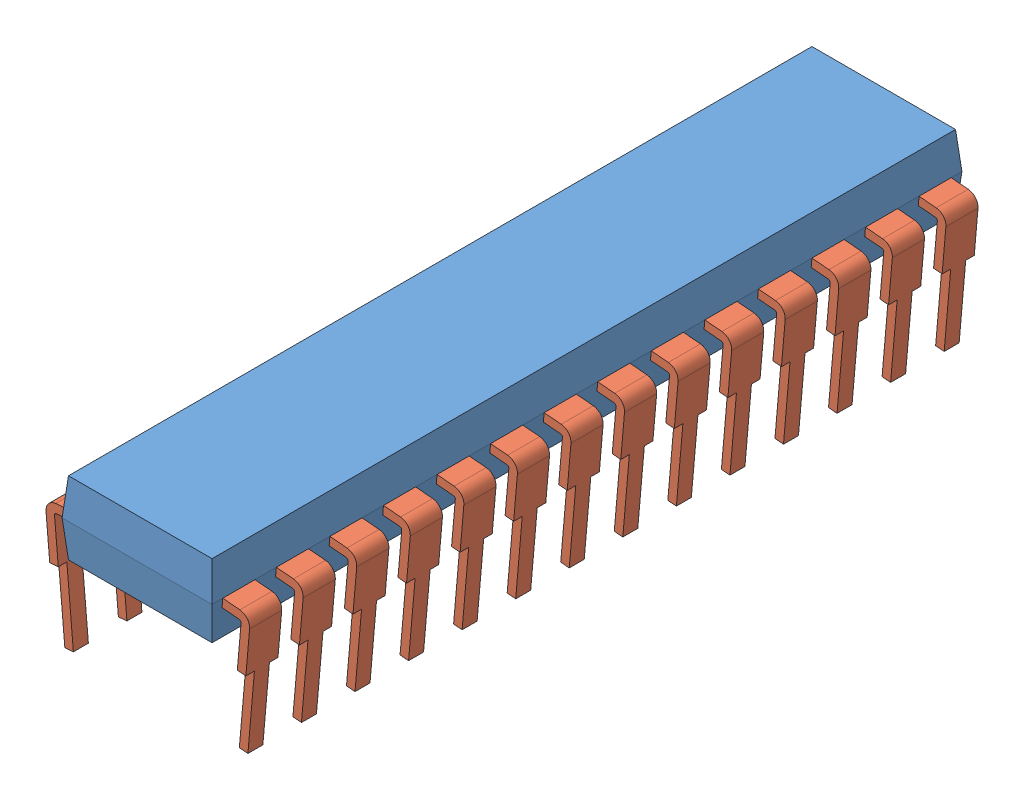
SolidWorks assembly Assem1, configuration Default. Lengths in mm.
Overall size (9.59 7.79 35).
29 component instances, 2 part files, 6 mates.
Components (placement in the parent):
- pin1-1: pin1 [Default] at (7.7092 18.3263 45.3028) size (7 3.4 35)
- pin2-1: pin2 [Default] at (13.0157 18.4744 43.3028) x (0.996195 -0.087156 0) z (0 0 1) size (3 6 1.5)
- pin2-34: pin2 [Default] at (13.0157 18.4744 40.8028) x (0.996195 -0.087156 0) z (0 0 1) size (3 6 1.5)
- pin2-35: pin2 [Default] at (13.0157 18.4744 38.3028) x (0.996195 -0.087156 0) z (0 0 1) size (3 6 1.5)
- pin2-36: pin2 [Default] at (13.0157 18.4744 35.8028) x (0.996195 -0.087156 0) z (0 0 1) size (3 6 1.5)
- pin2-37: pin2 [Default] at (13.0157 18.4744 33.3028) x (0.996195 -0.087156 0) z (0 0 1) size (3 6 1.5)
- pin2-38: pin2 [Default] at (13.0157 18.4744 30.8028) x (0.996195 -0.087156 0) z (0 0 1) size (3 6 1.5)
- pin2-39: pin2 [Default] at (13.0157 18.4744 28.3028) x (0.996195 -0.087156 0) z (0 0 1) size (3 6 1.5)
- pin2-40: pin2 [Default] at (13.0157 18.4744 25.8028) x (0.996195 -0.087156 0) z (0 0 1) size (3 6 1.5)
- pin2-41: pin2 [Default] at (13.0157 18.4744 23.3028) x (0.996195 -0.087156 0) z (0 0 1) size (3 6 1.5)
- pin2-42: pin2 [Default] at (13.0157 18.4744 20.8028) x (0.996195 -0.087156 0) z (0 0 1) size (3 6 1.5)
- pin2-43: pin2 [Default] at (13.0157 18.4744 18.3028) x (0.996195 -0.087156 0) z (0 0 1) size (3 6 1.5)
- pin2-44: pin2 [Default] at (13.0157 18.4744 15.8028) x (0.996195 -0.087156 0) z (0 0 1) size (3 6 1.5)
- pin2-45: pin2 [Default] at (13.0157 18.4744 13.3028) x (0.996195 -0.087156 0) z (0 0 1) size (3 6 1.5)
- pin2-46: pin2 [Default] at (13.0157 18.4744 10.8028) x (0.996195 -0.087156 0) z (0 0 1) size (3 6 1.5)
- pin2-49: pin2 [Default] at (9.4028 18.4744 44.8028) x (-0.996195 -0.087156 0) z (0 0 -1) size (3 6 1.5)
- pin2-50: pin2 [Default] at (9.4028 18.4744 42.3028) x (-0.996195 -0.087156 0) z (0 0 -1) size (3 6 1.5)
- pin2-51: pin2 [Default] at (9.4028 18.4744 39.8028) x (-0.996195 -0.087156 0) z (0 0 -1) size (3 6 1.5)
- pin2-52: pin2 [Default] at (9.4028 18.4744 37.3028) x (-0.996195 -0.087156 0) z (0 0 -1) size (3 6 1.5)
- pin2-53: pin2 [Default] at (9.4028 18.4744 34.8028) x (-0.996195 -0.087156 0) z (0 0 -1) size (3 6 1.5)
- pin2-54: pin2 [Default] at (9.4028 18.4744 32.3028) x (-0.996195 -0.087156 0) z (0 0 -1) size (3 6 1.5)
- pin2-55: pin2 [Default] at (9.4028 18.4744 29.8028) x (-0.996195 -0.087156 0) z (0 0 -1) size (3 6 1.5)
- pin2-56: pin2 [Default] at (9.4028 18.4744 27.3028) x (-0.996195 -0.087156 0) z (0 0 -1) size (3 6 1.5)
- pin2-57: pin2 [Default] at (9.4028 18.4744 24.8028) x (-0.996195 -0.087156 0) z (0 0 -1) size (3 6 1.5)
- pin2-58: pin2 [Default] at (9.4028 18.4744 22.3028) x (-0.996195 -0.087156 0) z (0 0 -1) size (3 6 1.5)
- pin2-59: pin2 [Default] at (9.4028 18.4744 19.8028) x (-0.996195 -0.087156 0) z (0 0 -1) size (3 6 1.5)
- pin2-60: pin2 [Default] at (9.4028 18.4744 17.3028) x (-0.996195 -0.087156 0) z (0 0 -1) size (3 6 1.5)
- pin2-61: pin2 [Default] at (9.4028 18.4744 14.8028) x (-0.996195 -0.087156 0) z (0 0 -1) size (3 6 1.5)
- pin2-62: pin2 [Default] at (9.4028 18.4744 12.3028) x (-0.996195 -0.087156 0) z (0 0 -1) size (3 6 1.5)
Mates (geometry in assembly coordinates):
- Distance3: distance = 0 mm anti-aligned: plane of pin2-1 through (13.0157 18.4744 44.8028) normal (-0.996195 0.087156 0); plane of pin1-1 through (12.9625 17.8667 45.3028) normal (0.996195 -0.087156 0)
- Coincident15: coincident anti-aligned: plane of pin1-1 through (13.0157 18.4744 44.8028) normal (-0.087156 -0.996195 0); plane of pin2-1 through (13.0157 18.4744 44.8028) normal (0.087156 0.996195 0)
- Coincident17: coincident anti-aligned: plane of pin1-1 through (13.0157 18.4744 44.8028) normal (0 0 -1); plane of pin2-1 through (15.4626 17.7585 44.8028) normal (0 0 1)
- Coincident23: coincident anti-aligned: plane of pin1-1 through (9.4559 17.8667 45.3028) normal (-0.996195 -0.087156 0); plane of pin2-49 through (9.4028 18.4744 43.3028) normal (0.996195 0.087156 0)
- Coincident24: coincident anti-aligned: plane of pin1-1 through (9.4028 18.4744 44.8028) normal (0.087156 -0.996195 0); plane of pin2-49 through (9.4028 18.4744 43.3028) normal (-0.087156 0.996195 0)
- Coincident25: coincident anti-aligned: plane of pin1-1 through (9.4028 18.4744 44.8028) normal (0 0 -1); plane of pin2-49 through (6.9559 17.7585 44.8028) normal (0 0 1)
